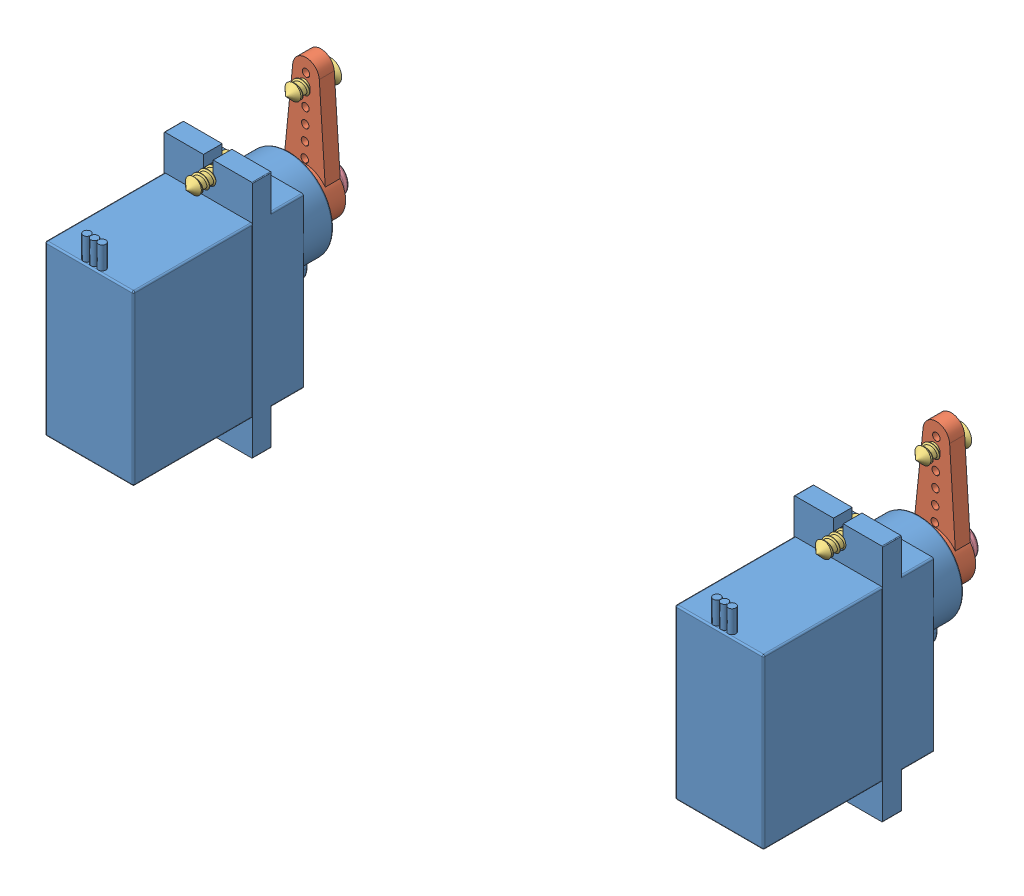
SolidWorks assembly PU, configuration Predeterminado. Lengths in mm.
Overall size (95.94 37.23 33.31).
12 component instances, 4 part files, 12 mates.
Components (placement in the parent):
- sg90-1: sg90 [Default] at (201.5956 -166.7354 155.7219) x (0 -1 0) z (1 0 0) size (31.9 29.9 11.8)
- sg90-2: sg90 [Default] at (117.452 -166.7354 155.7219) x (0 -1 0) z (1 0 0) size (31.9 29.9 11.8)
- SG90 plastic Horn-1: SG90 plastic Horn [Default] at (123.352 -172.6354 127.0219) x (0.017141 0.999853 0) z (-0.999853 0.017141 0) size (19.4 4 7.07)
- SG90 plastic Horn-2: SG90 plastic Horn [Default] at (207.4956 -172.6354 127.0219) x (0.020276 0.999794 0) z (-0.999794 0.020276 0) size (19.4 4 7.07)
- M2x6 SelfTap Screw-1: M2x6 SelfTap Screw [Predeterminado] at (207.4956 -164.3354 136.8219) x (-0.923728 -0.383049 0) z (0 0 -1) size (3.4 3.28 6)
- M2x6 SelfTap Screw-2: M2x6 SelfTap Screw [Predeterminado] at (207.4956 -191.6354 136.3219) x (-0.923728 -0.383049 0) z (0 0 -1) size (3.4 3.28 6)
- M2x6 SelfTap Screw-3: M2x6 SelfTap Screw [Predeterminado] at (123.352 -164.3354 136.8219) x (-0.993348 0.115149 0) z (0 0 -1) size (3.4 3.28 6)
- M2x6 SelfTap Screw-4: M2x6 SelfTap Screw [Predeterminado] at (123.352 -191.6354 136.8219) x (-0.923728 -0.383049 0) z (0 0 -1) size (3.4 3.28 6)
- (M2_3_mm)_90116A007_METRIC 316 SS PAN HEAD PHILLIPS MACHINE SCREW-1: (M2_3_mm)_90116A007_METRIC 316 SS PAN HEAD PHILLIPS MACHINE SCREW [90116A007] at (123.352 -172.6354 127.0219) x (-0.923728 -0.383049 0) z (0 0 -1) size (4 4 4.68)
- (M2_3_mm)_90116A007_METRIC 316 SS PAN HEAD PHILLIPS MACHINE SCREW-2: (M2_3_mm)_90116A007_METRIC 316 SS PAN HEAD PHILLIPS MACHINE SCREW [90116A007] at (207.4956 -172.6354 127.0219) x (-0.923728 -0.383049 0) z (0 0 -1) size (4 4 4.68)
- M2x6 SelfTap Screw-5: M2x6 SelfTap Screw [Predeterminado] at (123.352 -160.1354 123.5219) x (-0.923728 -0.383049 0) z (0 0 -1) size (3.4 3.28 6)
- M2x6 SelfTap Screw-6: M2x6 SelfTap Screw [Predeterminado] at (207.4956 -160.1354 123.5219) x (-0.923728 -0.383049 0) z (0 0 -1) size (3.4 3.28 6)
Mates (geometry in assembly coordinates):
- Coincidente326: coincident: plane of sg90-1 through (207.4956 -172.6354 129.0219) normal (0 0 -1); plane of SG90 plastic Horn-2 through (207.5438 -170.2609 129.0219) normal (0 0 1)
- Concéntrica163: concentric: circle of sg90-1; circle of SG90 plastic Horn-2
- Distancia47: distance = 0.5 mm: plane of M2x6 SelfTap Screw-1 through (207.4956 -164.3354 136.8219) normal (0 0 -1); plane of sg90-1 through (201.5956 -162.0354 137.3219) normal (0 0 -1)
- Concéntrica166: concentric: circle of sg90-1; circle of M2x6 SelfTap Screw-1
- Distancia48: distance = 1 mm: plane of M2x6 SelfTap Screw-2 through (207.4956 -191.6354 136.3219) normal (0 0 -1); plane of sg90-1 through (213.3956 -193.9354 137.3219) normal (0 0 -1)
- Concéntrica167: concentric: circle of sg90-1; circle of M2x6 SelfTap Screw-2
- Coincidente325: coincident: plane of sg90-2 through (123.352 -172.6354 129.0219) normal (0 0 -1); plane of SG90 plastic Horn-1 through (123.3927 -170.2608 129.0219) normal (0 0 1)
- Concéntrica162: concentric: circle of sg90-2; circle of SG90 plastic Horn-1
- Distancia49: distance = 0.5 mm: plane of M2x6 SelfTap Screw-3 through (123.352 -164.3354 136.8219) normal (0 0 -1); plane of sg90-2 through (117.452 -162.0354 137.3219) normal (0 0 -1)
- Concéntrica168: concentric: circle of sg90-2; circle of M2x6 SelfTap Screw-3
- Distancia50: distance = 0.5 mm: plane of M2x6 SelfTap Screw-4 through (123.352 -191.6354 136.8219) normal (0 0 -1); plane of sg90-2 through (129.252 -193.9354 137.3219) normal (0 0 -1)
- Concéntrica169: concentric: circle of sg90-2; circle of M2x6 SelfTap Screw-4
